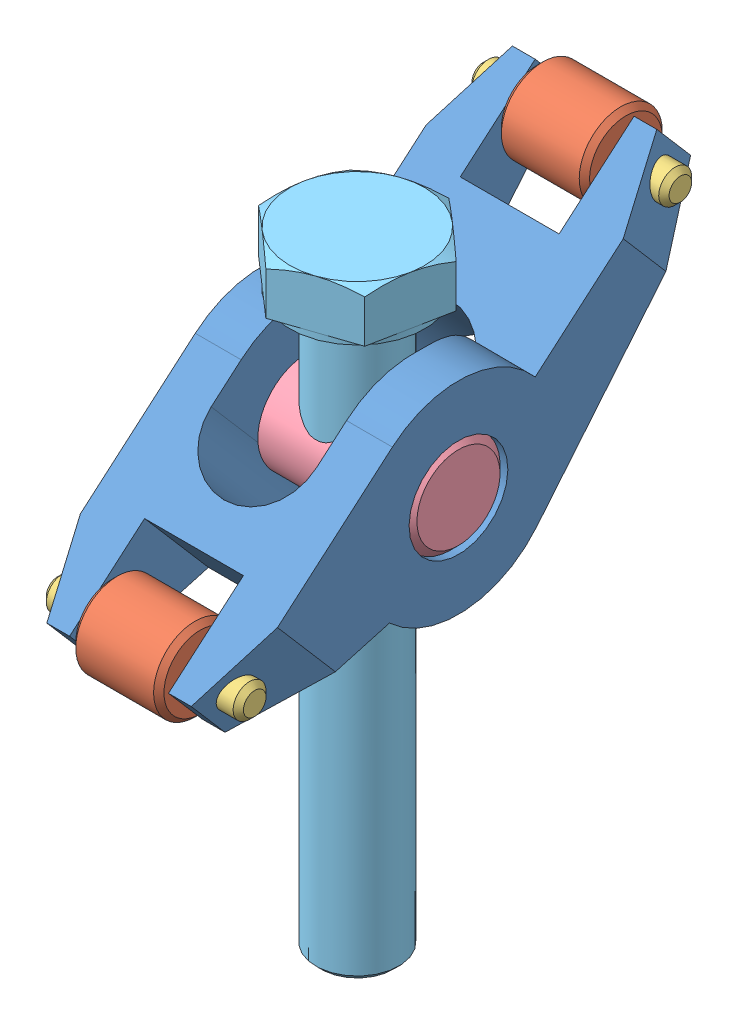
SolidWorks assembly rockerarmassembly, configuration Default. Lengths in mm.
Overall size (19.86 68.34 51.67).
7 component instances, 5 part files, 12 mates.
Components (placement in the parent):
- rockerarm-1: rockerarm [Default] at (74.1317 19.2888 3.6952) x (1 0 0) z (0 -0.652291 0.757968) size (19 19.53 50.8)
- rockerarm_campusher-1: rockerarm_campusher [Default] at (74.1317 34.346 -17.6953) size (8.5 8 8)
- rockerarm_pin-1: rockerarm_pin [Default] at (74.1317 11.9215 23.3324) x (0 -1 0) z (0 0 1) size (3.18 19 3.18)
- rockerarm_holder-1: rockerarm_holder [Default] at (74.1317 19.2888 3.6952) size (19 9.53 9.53)
- rockerarm_pin-2: rockerarm_pin [Default] at (74.1317 34.346 -17.6953) x (0 -1 0) z (0 0 1) size (3.18 19 3.18)
- rockerarm_campusher-2: rockerarm_campusher [Default] at (74.1317 11.9215 23.3324) size (8.5 8 8)
- hex screw gradeab fine_iso-1: hex screw gradeab fine_iso [PreviewCfg] at (74.1317 37.2888 3.9452) x (0 -1 0) z (-0.657945 0 0.753066) size (105 41.57 36)
Mates (geometry in assembly coordinates):
- Concentric1: concentric aligned: cylinder of rockerarm-1 through (83.6317 19.2888 3.6952) axis (-1 0 0) radius 4.765; cylinder of rockerarm_holder-1 through (83.6317 19.2888 3.6952) axis (-1 0 0) radius 4.765
- Coincident1: coincident aligned: plane of rockerarm-1 through (83.6317 19.2888 3.6952) normal (1 0 0); plane of rockerarm_holder-1 through (83.6317 19.2888 3.6952) normal (1 0 0)
- Concentric2: concentric anti-aligned: cylinder of rockerarm-1 through (64.6317 11.9215 23.3324) axis (1 0 0) radius 1.59; cylinder of rockerarm_pin-1 through (83.6317 11.9215 23.3324) axis (-1 0 0) radius 1.59
- Concentric3: concentric anti-aligned: circle of rockerarm-1; circle of rockerarm_campusher-2
- Width1: width anti-aligned: plane of rockerarm_campusher-2 through (69.8817 11.9215 23.3324) normal (-1 0 0); plane of rockerarm-1 through (78.3817 11.9215 23.3324) normal (1 0 0); plane of rockerarm_campusher-2 through (69.3667 3.6032 6.9518) normal (1 0 0); plane of rockerarm-1 through (78.8967 3.6032 6.9518) normal (-1 0 0)
- Coincident4: coincident aligned: plane of rockerarm-1 through (83.6317 19.2888 3.6952) normal (1 0 0); plane of rockerarm_pin-1 through (83.6317 11.9215 23.3324) normal (1 0 0)
- Concentric4: concentric anti-aligned: cylinder of rockerarm-1 through (64.6317 34.346 -17.6953) axis (1 0 0) radius 1.59; cylinder of rockerarm_pin-2 through (83.6317 34.346 -17.6953) axis (-1 0 0) radius 1.59
- Coincident5: coincident aligned: plane of rockerarm-1 through (83.6317 19.2888 3.6952) normal (1 0 0); plane of rockerarm_pin-2 through (83.6317 34.346 -17.6953) normal (1 0 0)
- Width2: width anti-aligned: plane of rockerarm_campusher-1 through (78.3817 34.346 -17.6953) normal (1 0 0); plane of rockerarm-1 through (69.8817 34.346 -17.6953) normal (-1 0 0); plane of rockerarm_campusher-1 through (78.8967 24.3102 -17.1099) normal (-1 0 0); plane of rockerarm-1 through (69.3667 24.3102 -17.1099) normal (1 0 0)
- Concentric5: concentric aligned: cylinder of rockerarm_campusher-1 through (78.3817 34.346 -17.6953) axis (-1 0 0) radius 1.59; cylinder of rockerarm_pin-2 through (83.6317 34.346 -17.6953) axis (-1 0 0) radius 1.59
- Concentric6: concentric aligned: cylinder of rockerarm_holder-1 through (74.1317 14.5238 3.9452) axis (0 1 0) radius 3.43; cylinder of hex screw gradeab fine_iso-1 through (74.1317 37.2888 3.9452) axis (0 1 0) radius 4
- Distance1: distance = 12.7 mm anti-aligned: plane of rockerarm_holder-1 through (74.1317 19.2888 3.6952) normal (0 1 0); plane of hex screw gradeab fine_iso-1 through (79.7838 31.9888 8.8834) normal (0 -1 0)
